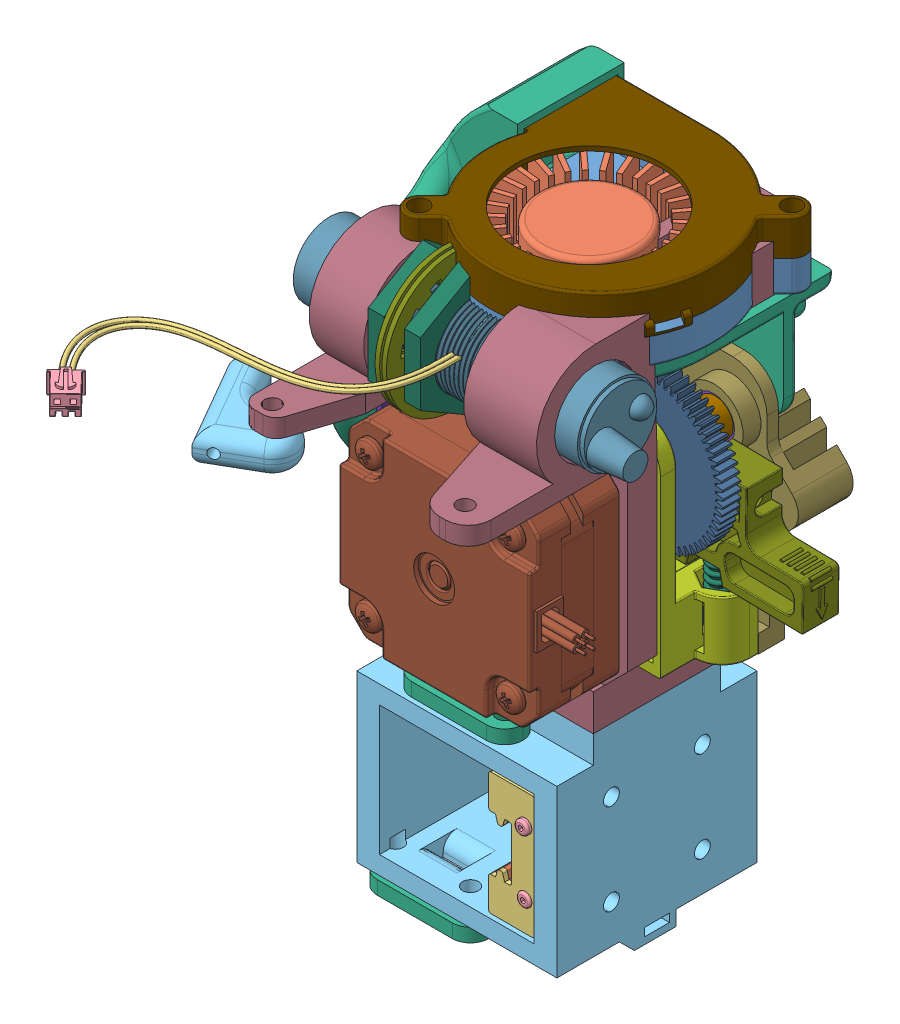
SolidWorks assembly X_Assembly_fan1, configuration Default. Lengths in mm.
Overall size (91.99 134.1 127.07).
68 component instances, 43 part files, 46 mates.
Components (placement in the parent):
- BlockAssem-1: BlockAssem [Default] at origin size (10 27 45.5)
  - Main Block-1: Main Block [Default] at (169.1827 226.6144 359.262) x (0 0 1) z (1 0 0) size (32 27 10)
  - Green End Cap-1: Green End Cap [Default] at (174.1827 226.6144 343.262) x (0 1 0) z (0 0 -1) size (27 10 5)
  - Red End Cap-1: Red End Cap [Default] at (174.1827 226.6144 338.262) x (0 1 0) z (0 0 -1) size (27 10 1)
  - Green End Cap-2: Green End Cap [Default] at (174.1827 226.6144 375.262) x (0 -1 0) z (0 0 1) size (27 10 5)
  - Red End Cap-2: Red End Cap [Default] at (174.1827 226.6144 380.262) x (0 -1 0) z (0 0 1) size (27 10 1)
  - Button M3x8-1: Button M3x8 [Default] at (177.1827 219.6144 381.762) x (0.381849 -0.924225 0) z (0 0 -1) size (3 3 7)
  - Button M3x8-2: Button M3x8 [Default] at (177.1827 233.6144 382.262) x (0.381849 -0.924225 0) z (0 0 -1) size (3 3 7)
  - Button M3x8-3: Button M3x8 [Default] at (177.1827 219.6144 336.762) x (-0.381849 0.924225 0) z (0 0 1) size (3 3 7)
  - Button M3x8-5: Button M3x8 [Default] at (177.1827 233.6144 336.762) x (-0.381849 0.924225 0) z (0 0 1) size (3 3 7)
- X_Carriadge-1: X_Carriadge [Default] at (179.1827 224.5695 363.3255) x (0 0 -1) z (0 -1 0) size (44 46 45.8)
- BeltClamp-1: BeltClamp [Default] at (156.1827 203.4844 345.262) x (0 -1 0) z (0 0 1) size (3 24.5 8)
- BeltClamp-2: BeltClamp [Default] at (148.6827 203.4844 381.262) x (0 -1 0) z (0 0 1) size (3 24.5 8)
- BeltClamp-3: BeltClamp [Default] at (157.1827 244.9844 337.262) x (0 -1 0) z (0 0 -1) size (3 24.5 8)
- BeltClamp-4: BeltClamp [Default] at (156.1827 244.9844 381.262) x (0 -1 0) z (0 0 1) size (3 24.5 8)
- e3d titan areo 1.75-1: e3d titan areo 1.75 [Default] at (166.6827 280.1144 364.262) x (0 -1 0) z (1 0 0) size (64.3 55.51 89.93)
  - e3d titan areo 1.75.step-1: e3d titan areo 1.75.step [Default] at origin size (64.3 55.51 89.93)
    - Base.step-1: Base.step [Default] at origin size (46 23.41 49.98)
    - 9x5x3mm bearing.step-1: 9x5x3mm bearing.step [Default] at (-15.5 4 15.5) x (1 0 0) z (0 -1 0) size (9 9 3)
    - hobbed wheel.step-1: hobbed wheel.step [Default] at (-15.5 1.6 15.5) x (-0.447437 0 0.894315) z (0 1 0) size (8.6 8.58 20.6)
    - filament gear.step-1: filament gear.step [Default] at (-15.5 8.55 15.5) x (-0.894315 0 -0.447437) z (0 -1 0) size (34 34 4)
    - motor gear.step-1: motor gear.step [Default] at (0 8.5 0) x (-0.681998 0 -0.731354) z (0 -1 0) size (11.99 12.02 9)
    - cover.step-1: cover.step [Default] at (0 24.9 0) x (1 0 0) z (0 0 -1) size (52.63 28.16 55.14)
    - 9x5x3mm bearing.step-2: 9x5x3mm bearing.step [Default] at (-15.5 22.8 15.5) x (1 0 0) z (0 -1 0) size (9 9 3)
    - m3x8.step-1: m3x8.step [Default] at (20.7 13.6 23.3) x (0 0 1) z (0 1 0) size (5.69 9.65 5.69)
    - M3 nut.step-1: M3 nut.step [Default] at (16.7 13.6 23.3) x (0 1 0) z (0 0 1) size (5.49 2.44 6.31)
    - idler spring.step-1: idler spring.step [Default] at (14.287 13.6 23.3) x (0 0 1) z (-1 0 0) size (6.44 6.46 12.03)
    - tensioner.step-1: tensioner.step [Default] at (0 13.6 0) x (0 -1 0) z (0.017452 0 0.999848) size (8.2 21.5 50.88)
    - idler bearing pin.step-1: idler bearing pin.step [Default] at (-5.2287 9.6 15.5936) x (0.999848 0 -0.017452) z (0 1 0) size (3 3 9)
    - idler bearing.step-1: idler bearing.step [Default] at (-5.2287 13.6 15.5936) x (0.999848 0 -0.017452) z (0 1 0) size (10 10 4)
    - guide tube.step-1: guide tube.step [Default] at (-10.9 13.6 -7.9) x (-1 0 0) z (0 0 1) size (10.9 16.1 22.03)
    - ISO 7380 - M3 x 28 v1.step-1: ISO 7380 - M3 x 28 v1.step [Default] at (-15.5 25.94 15.5) x (0 -1 0) z (0 0 1) size (14.65 5.7 5.7)
    - ISO 7380 - M3 x 28 v1.step-2: ISO 7380 - M3 x 28 v1.step [Default] at (15.5 25.94 15.5) x (0 -1 0) z (0 0 1) size (14.65 5.7 5.7)
    - ISO 7380 - M3 x 28 v1.step-3: ISO 7380 - M3 x 28 v1.step [Default] at (15.5 25.94 -15.5) x (0 -1 0) z (0 0 1) size (14.65 5.7 5.7)
    - ISO 7380 - M3 x 28 v1.step-4: ISO 7380 - M3 x 28 v1.step [Default] at (-21.7 25.94 -14.7) x (0 -1 0) z (0 0 -1) size (14.65 5.7 5.7)
    - Fan 40 X 40 X 10 v4.step-1: Fan 40 X 40 X 10 v4.step [Default] at (-2.3 40.465 3.8274) x (0.707107 0 0.707107) z (-0.707107 0 0.707107) size (40 10.58 40) (hidden)
    - E3D v6 HotEnd - Heatbreak.step-1: E3D v6 HotEnd - Heatbreak.step [Default] at (-10.9 13.6 -31.7812) x (0 1 0) z (0 0 -1) size (7 7 21.9)
    - E3D v6 HotEnd - Nozzle.step-1: E3D v6 HotEnd - Nozzle.step [Default] at (-10.9 13.6 -42.2812) x (0 1 0) z (0 0 -1) size (8.08 7 12.5)
    - E3D v6 HotEnd - Heat Block.step-1: E3D v6 HotEnd - Heat Block.step [Default] at (-2.9 -1.9 -38.0312) x (0 1 0) z (1 0 0) size (20 11.5 16)
    - Ceramic Cartridge Heater.step-1: Ceramic Cartridge Heater.step [Default] at (-0.9 6.6 -34.0312) x (0 0 1) z (1 0 0) size (6 18 29.25)
    - Thermistor.step-1: Thermistor.step [Default] at (-7 16.1 -36.0312) x (0 -0.5 0.866025) z (-1 0 0) size (1.5 1.5 7.6)
    - HEXAGON SOCKET HEAD CAP SCREWS_SCB3-4.step-1: HEXAGON SOCKET HEAD CAP SCREWS_SCB3-4.step [Default] at (-2.4 14.6 -33.2312) x (0 1 0) z (1 0 0) size (5.5 5.5 7)
    - HEXAGON SOCKET HEAD CAP SCREWS_SCB3-10.step-1: HEXAGON SOCKET HEAD CAP SCREWS_SCB3-10.step [Default] at (-10.9 0.6 -38.0312) x (0 1 0) z (0 0 -1) size (5.5 5.5 13)
    - Flat Washers_PWF3.step-1: Flat Washers_PWF3.step [Default] at (-2.4 14.6 -33.2312) x (0 1 0) z (1 0 0) size (6 6 0.5)
    - ISO 7380 - M3 x 28 v1.step-5: ISO 7380 - M3 x 28 v1.step [Default] at (-2.3 45.465 26.4548) x (0 -1 0) z (0.707107 0 0.707107) size (14.65 5.7 5.7) (hidden)
    - ISO 7380 - M3 x 28 v1.step-6: ISO 7380 - M3 x 28 v1.step [Default] at (-24.9274 45.465 3.8274) x (0 -1 0) z (0.707107 0 0.707107) size (14.65 5.7 5.7) (hidden)
    - ISO 7380 - M3 x 28 v1.step-7: ISO 7380 - M3 x 28 v1.step [Default] at (-2.3 45.465 -18.8) x (0 -1 0) z (0.707107 0 0.707107) size (14.65 5.7 5.7) (hidden)
    - ISO 7380 - M3 x 28 v1.step-8: ISO 7380 - M3 x 28 v1.step [Default] at (20.3274 45.465 3.8274) x (0 -1 0) z (0.707107 0 0.707107) size (14.65 5.7 5.7) (hidden)
- Nema17Pancake-1: Nema17Pancake [По умолчанию] at (166.6827 280.1144 390.762) x (0 -1 0) z (1 0 0) size (42 40 51.2)
- endstop-1: endstop [Default] at (138.1827 224.3644 346.262) x (0 -1 0) z (1 0 0) size (39.5 18.65 8)
- ExtruderMount18-1: ExtruderMount18 [Default] at (140.1827 250.6144 370.762) x (0 0 1) z (-1 0 0) size (76 86 50)
- LJ18A3-1: LJ18A3 [Default] at (139.6827 316.6144 377.762) x (0 0.776316 -0.630344) z (1 0 0) size (30 30 71.4)
  - LJ18A3.step-1: LJ18A3.step [Default] at origin size (30 30 71.4)
    - Sensor.step-1: Sensor.step [Default] at origin size (18.25 18.25 71.4)
    - Nut.step-1: Nut.step [Default] at (69.0679 5.4432 19.5) size (25.89 27.37 3.53)
    - Spacer.step-1: Spacer.step [Default] at (163.1041 9.6725 17.5) size (30 30 1)
    - Nut.step-2: Nut.step [Default] at (69.0679 5.4432 11.5) size (25.89 27.37 3.53)
    - Spacer.step-2: Spacer.step [Default] at (163.1041 9.6725 16) size (30 30 1)
- LedRing-1: LedRing [Default] at (141.1827 286.6144 348.762) x (0 -1 0) z (0 0 1) size (60 1 60)
- DuctFan_12v-1: DuctFan_12v [Default] at (166.4958 319.3443 355.6939) x (-0.999986 0 -0.005255) z (0.005255 0 -0.999986) size (71.63 17.56 112.02)
  - fan_12v.step-1: fan_12v.step [Default] at origin size (71.63 17.56 112.02)
    - corpo_topo.step-1: corpo_topo.step [Default] at origin size (51.07 9.32 51.81)
    - corpo_base.step-1: corpo_base.step [Default] at origin size (50.9 8.01 51.63)
    - blade.step-1: blade.step [Default] at origin size (40.62 11 40.62)
    - cabo.step-1: cabo.step [Default] at origin size (46.95 2.25 68.66)
    - conector.step-1: conector.step [Default] at origin size (8.74 5 8.77)
- Coper tube holder-1: Coper tube holder [Default] at (143.0929 296.6144 402.762) x (0 1 0) z (-0.129812 0 -0.991539) size (7.46 22.06 22.77)
- AeroFanShroud-1: AeroFanShroud [Default] at (193.0542 319.3443 377.4182) x (-1 0 0) z (0 -1 0) size (65.05 67.51 71.83)
Mates (geometry in assembly coordinates):
- Concentric1: concentric anti-aligned: cylinder of BlockAssem-1/Main Block-1 through (174.1827 236.6144 369.262) axis (1 0 0) radius 1.35; cylinder of X_Carriadge-1 through (184.1827 236.6144 369.262) axis (-1 0 0) radius 1.75
- Concentric2: concentric anti-aligned: cylinder of BlockAssem-1/Main Block-1 through (174.1827 216.6144 369.262) axis (1 0 0) radius 1.375; cylinder of X_Carriadge-1 through (184.1827 216.6144 369.262) axis (-1 0 0) radius 1.75
- Coincident1: coincident anti-aligned: plane of BlockAssem-1/Green End Cap-2 through (179.1827 240.1144 380.262) normal (1 0 0); plane of X_Carriadge-1 through (179.1827 224.5695 363.3255) normal (-1 0 0)
- Concentric3: concentric aligned: cylinder of X_Carriadge-1 through (152.1827 214.1144 341.262) axis (0 -1 0) radius 1.6945; cylinder of BeltClamp-1 through (152.1827 207.1144 341.262) axis (0 -1 0) radius 1.75
- Concentric4: concentric aligned: cylinder of X_Carriadge-1 through (168.6827 214.1144 341.262) axis (0 -1 0) radius 1.6235; cylinder of BeltClamp-1 through (168.6827 207.1144 341.262) axis (0 -1 0) radius 1.75
- Distance1: distance = 1 mm anti-aligned: plane of X_Carriadge-1 through (184.1827 208.1144 381.262) normal (0 -1 0); plane of BeltClamp-1 through (156.1827 207.1144 345.262) normal (0 1 0)
- Concentric5: concentric aligned: cylinder of X_Carriadge-1 through (144.6827 214.1144 377.262) axis (0 -1 0) radius 1.75; cylinder of BeltClamp-2 through (144.6827 207.1144 377.262) axis (0 -1 0) radius 1.75
- Concentric6: concentric aligned: cylinder of X_Carriadge-1 through (161.1827 214.1144 377.262) axis (0 -1 0) radius 1.75; cylinder of BeltClamp-2 through (161.1827 207.1144 377.262) axis (0 -1 0) radius 1.75
- Distance2: distance = 1 mm anti-aligned: plane of X_Carriadge-1 through (184.1827 208.1144 381.262) normal (0 -1 0); plane of BeltClamp-2 through (148.6827 207.1144 381.262) normal (0 1 0)
- Concentric7: concentric anti-aligned: cylinder of X_Carriadge-1 through (144.6827 238.6144 341.262) axis (0 1 0) radius 1.75; cylinder of BeltClamp-3 through (144.6827 248.6144 341.262) axis (0 -1 0) radius 1.75
- Concentric8: concentric anti-aligned: cylinder of X_Carriadge-1 through (161.1827 238.6144 341.262) axis (0 1 0) radius 1.75; cylinder of BeltClamp-3 through (161.1827 248.6144 341.262) axis (0 -1 0) radius 1.75
- Distance3: distance = 1 mm anti-aligned: plane of X_Carriadge-1 through (184.1827 244.6144 381.262) normal (0 1 0); plane of BeltClamp-3 through (148.6827 245.6144 337.262) normal (0 -1 0)
- Concentric9: concentric anti-aligned: cylinder of X_Carriadge-1 through (152.1827 238.6144 377.262) axis (0 1 0) radius 1.75; cylinder of BeltClamp-4 through (152.1827 248.6144 377.262) axis (0 -1 0) radius 1.75
- Concentric10: concentric anti-aligned: cylinder of X_Carriadge-1 through (168.6827 238.6144 377.262) axis (0 1 0) radius 1.75; cylinder of BeltClamp-4 through (168.6827 248.6144 377.262) axis (0 -1 0) radius 1.75
- Distance4: distance = 1 mm anti-aligned: plane of X_Carriadge-1 through (184.1827 244.6144 381.262) normal (0 1 0); plane of BeltClamp-4 through (164.6827 245.6144 381.262) normal (0 -1 0)
- Parallel1: parallel anti-aligned: plane of X_Carriadge-1 through (184.1827 244.6144 337.262) normal (0 0 -1); plane of e3d titan areo 1.75-1/e3d titan areo 1.75.step-1/Base.step-1 through (167.9827 282.4144 364.262) normal (0 0 1)
- Parallel2: parallel aligned: plane of X_Carriadge-1 through (184.1827 224.5695 363.3255) normal (1 0 0); plane of e3d titan areo 1.75-1/e3d titan areo 1.75.step-1/Base.step-1 through (189.9827 305.4144 364.262) normal (1 0 0)
- Concentric11: concentric aligned: cylinder of e3d titan areo 1.75-1/e3d titan areo 1.75.step-1/hobbed wheel.step-1 through (182.1827 295.6144 352.362) axis (0 0 1) radius 1.65; cylinder of Nema17Pancake-1 through (182.1827 295.6144 370.762) axis (0 0 1) radius 1.5
- Concentric12: concentric aligned: cylinder of e3d titan areo 1.75-1/e3d titan areo 1.75.step-1/Base.step-1 through (151.1827 264.6144 360.762) axis (0 0 1) radius 1.825; cylinder of Nema17Pancake-1 through (151.1827 264.6144 370.762) axis (0 0 1) radius 1.5
- Parallel3: parallel anti-aligned: plane of X_Carriadge-1 through (140.1827 224.5695 363.3255) normal (-1 0 0); plane of endstop-1 through (138.1827 224.3644 346.262) normal (1 0 0)
- Parallel4: parallel aligned: plane of X_Carriadge-1 through (184.1827 244.6144 337.262) normal (0 0 -1); plane of endstop-1 through (137.1827 236.6144 338.262) normal (0 0 -1)
- Concentric15: concentric anti-aligned: cylinder of X_Carriadge-1 through (138.1827 239.6144 341.262) axis (1 0 0) radius 2; cylinder of endstop-1 through (137.1827 239.6144 341.262) axis (-1 0 0) radius 1.6
- Coincident16: coincident anti-aligned: plane of X_Carriadge-1 through (138.1827 239.6144 341.262) normal (-1 0 0); plane of endstop-1 through (138.1827 224.3644 346.262) normal (1 0 0)
- Coincident17: coincident aligned: plane of X_Carriadge-1 through (180.1827 250.6144 349.262) normal (-1 0 0); plane of ExtruderMount18-1 through (180.1827 255.6144 349.262) normal (-1 0 0)
- Coincident18: coincident aligned: plane of X_Carriadge-1 through (170.1827 250.6144 349.262) normal (0 0 1); plane of ExtruderMount18-1 through (170.1827 255.6144 349.262) normal (0 0 1)
- Coincident19: coincident anti-aligned: plane of X_Carriadge-1 through (179.1827 250.6144 363.3255) normal (0 1 0); plane of ExtruderMount18-1 through (140.1827 250.6144 370.762) normal (0 -1 0)
- Concentric16: concentric anti-aligned: circle of Nema17Pancake-1; cylinder of ExtruderMount18-1 through (182.1827 295.6144 345.262) axis (0 0 1) radius 1.75
- Concentric17: concentric aligned: cylinder of Nema17Pancake-1 through (151.1827 295.6144 370.762) axis (0 0 1) radius 1.5; cylinder of ExtruderMount18-1 through (151.1827 295.6144 345.262) axis (0 0 1) radius 1.75
- Coincident20: coincident anti-aligned: plane of Nema17Pancake-1 through (166.6827 280.1144 370.762) normal (0 0 -1); plane of ExtruderMount18-1 through (140.1827 255.6144 370.762) normal (0 0 1)
- Coincident21: coincident anti-aligned: plane of e3d titan areo 1.75-1/e3d titan areo 1.75.step-1/Base.step-1 through (167.9827 282.4144 364.262) normal (0 0 1); plane of ExtruderMount18-1 through (184.1827 303.6144 364.262) normal (0 0 -1)
- Concentric18: concentric anti-aligned: cylinder of ExtruderMount18-1 through (151.1827 316.6144 377.762) axis (-1 0 0) radius 9; cylinder of LJ18A3-1/LJ18A3.step-1/Sensor.step-1 through (179.6827 316.6144 377.762) axis (1 0 0) radius 8.5
- Coincident23: coincident anti-aligned: plane of ExtruderMount18-1 through (151.1827 316.6144 377.762) normal (1 0 0); plane of LJ18A3-1/LJ18A3.step-1/Nut.step-2 through (151.1827 316.6144 377.762) normal (-1 0 0)
- Parallel5: parallel aligned: plane of Nema17Pancake-1 through (166.6827 280.1144 390.762) normal (0 0 1); plane of LJ18A3-1/LJ18A3.step-1/Nut.step-2 through (151.1827 323.5426 389.762) normal (0 0 1)
- Parallel6: parallel anti-aligned: plane of e3d titan areo 1.75-1/e3d titan areo 1.75.step-1/E3D v6 HotEnd - Heat Block.step-1 through (128.6515 283.0144 366.162) normal (-1 0 0); plane of LedRing-1 through (142.1827 286.6144 348.762) normal (1 0 0)
- Coincident25: coincident anti-aligned: plane of ExtruderMount18-1 through (142.1827 250.6144 370.762) normal (-1 0 0); plane of LedRing-1 through (142.1827 286.6144 348.762) normal (1 0 0)
- Concentric19: concentric anti-aligned: cylinder of ExtruderMount18-1 through (117.1827 286.6144 348.762) axis (1 0 0) radius 31.5; cylinder of LedRing-1 through (142.1827 286.6144 348.762) axis (-1 0 0) radius 30
- Concentric21: concentric anti-aligned: cylinder of ExtruderMount18-1 through (143.0929 294.6144 402.762) axis (0 1 0) radius 1.75; cylinder of Coper tube holder-1 through (143.0929 303.6144 402.762) axis (0 -1 0) radius 1.5
- Coincident27: coincident anti-aligned: plane of ExtruderMount18-1 through (151.1827 303.6144 364.262) normal (0 -1 0); plane of Coper tube holder-1 through (143.0929 303.6144 402.762) normal (0 1 0)
- Angle2: planar angle = 0.523599 rad anti-aligned: plane of Coper tube holder-1 through (130.6352 303.6144 390.4207) normal (-0.5 0 -0.866025); plane of Nema17Pancake-1 through (166.6827 280.1144 390.762) normal (0 0 1)
- Concentric22: concentric aligned: circle of e3d titan areo 1.75-1/e3d titan areo 1.75.step-1/ISO 7380 - M3 x 28 v1.step-1; cylinder of AeroFanShroud-1 through (182.1827 295.6144 338.322) axis (0 0 -1) radius 1.725
- Parallel7: parallel anti-aligned: cylinder of e3d titan areo 1.75-1/e3d titan areo 1.75.step-1/ISO 7380 - M3 x 28 v1.step-4 through (151.9827 301.8144 337.497) axis (0 0 1) radius 2.85; cylinder of AeroFanShroud-1 through (151.8207 301.845 338.322) axis (0 0 -1) radius 1.7208
- Coincident28: coincident anti-aligned: plane of e3d titan areo 1.75-1/e3d titan areo 1.75.step-1/cover.step-1 through (167.9827 282.4144 338.322) normal (0 0 -1); plane of AeroFanShroud-1 through (168.5542 305.8524 338.322) normal (0 0 1)
- Parallel9: parallel anti-aligned: plane of e3d titan areo 1.75-1/e3d titan areo 1.75.step-1/cover.step-1 through (189.9827 305.4144 339.362) normal (0 1 0); plane of AeroFanShroud-1 through (139.1731 316.3443 328.822) normal (0 -1 0)
- Coincident30: coincident: plane of DuctFan_12v-1/fan_12v.step-1/corpo_base.step-1 through (168.5294 319.3443 358.6116) normal (0 -1 0); plane of AeroFanShroud-1 through (148.0542 319.3443 338.322) normal (0 1 0)
- Coincident31: coincident: plane of DuctFan_12v-1/fan_12v.step-1/corpo_base.step-1 through (164.3749 319.3443 328.6884) normal (0 0 -1); plane of AeroFanShroud-1 through (141.4955 334.3443 328.6884) normal (0 0 1)
- Coincident32: coincident aligned: line of DuctFan_12v-1/fan_12v.step-1/corpo_base.step-1 through (141.4955 319.8443 328.6884) axis (0 1 0); line of AeroFanShroud-1 through (141.4955 319.3443 328.6884) axis (0 1 0)
